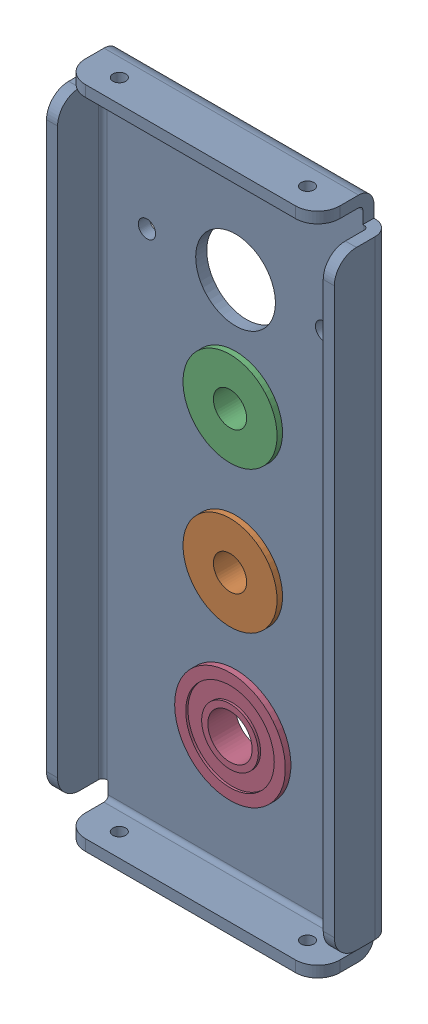
SolidWorks assembly ws_gearbox_plate_asm, configuration Default. Lengths in mm.
Overall size (82.55 190.5 19.29).
4 component instances, 3 part files, 0 mates.
Components (placement in the parent):
- ws_cim_plate_revc-1: ws_cim_plate_revc [Default] at origin size (82.55 190.5 16.12)
- brf-06-1: brf-06 [Default] at (0 56.4134 3.175) size (26.97 26.97 7.62)
- brf-06-2: brf-06 [Default] at (0 97.1296 3.175) size (26.97 26.97 7.62)
- brf-08-1: brf-08 [Default] at (0 15.6972 0.7937) size (31.75 31.75 7.94)
